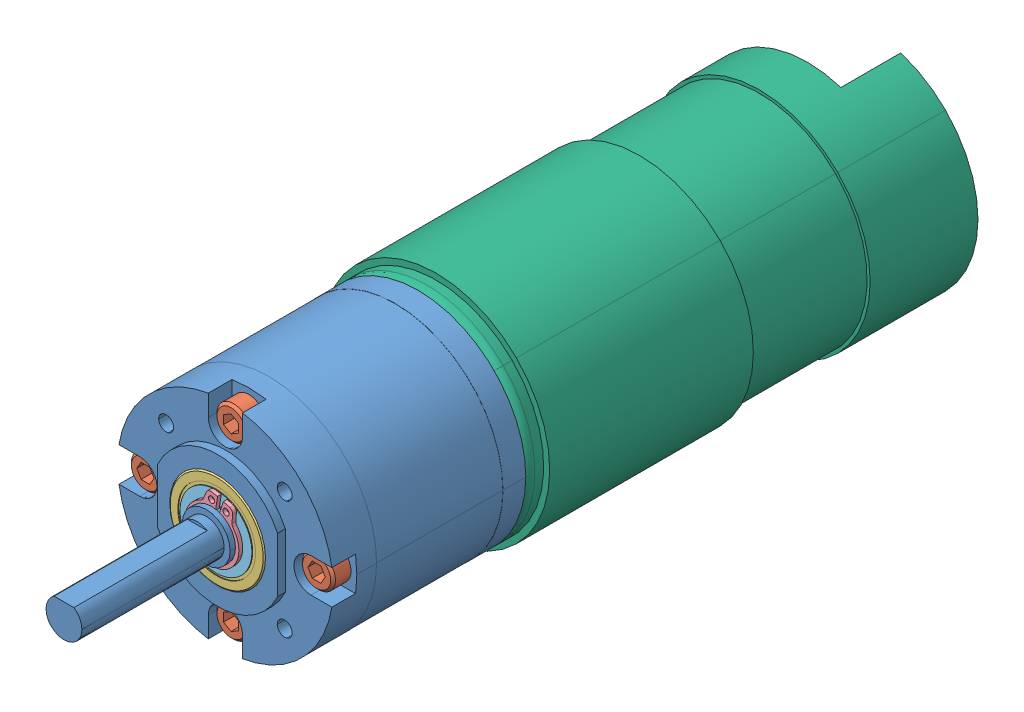
SolidWorks assembly am-3637+NeveRest+20+Orbital+Gearmotor (2).STEP, configuration Default. Lengths in mm.
Overall size (53.74 53.74 134.3).
9 component instances, 6 part files, 0 mates.
Components (placement in the parent):
- NeveRest orbital 2 stage Gearbox.STEP-1: NeveRest orbital 2 stage Gearbox.STEP [Default] at (-28.8441 -12.442 -2.3383) size (36 36 59.11)
- SHCS M3 x 16mm.STEP-1: SHCS M3 x 16mm.STEP [Default] at (-28.8441 1.8455 25.8811) size (5.5 5.5 19)
- SHCS M3 x 16mm.STEP-2: SHCS M3 x 16mm.STEP [Default] at (-14.5566 -12.442 25.8811) x (0 -1 0) z (0 0 1) size (5.5 5.5 19)
- SHCS M3 x 16mm.STEP-3: SHCS M3 x 16mm.STEP [Default] at (-28.8441 -26.7295 25.8811) x (-1 0 0) z (0 0 1) size (5.5 5.5 19)
- SHCS M3 x 16mm.STEP-4: SHCS M3 x 16mm.STEP [Default] at (-43.1316 -12.442 25.8811) x (0 1 0) z (0 0 1) size (5.5 5.5 19)
- 7804K117_STAINLESS STEEL BALL BEARING_7804K117.STEP-1: 7804K117_STAINLESS STEEL BALL BEARING_7804K117.STEP [Default] at (-28.8441 -12.442 28.7705) x (0.941717 0.336405 0) z (0 0 1) size (16 16 5)
- 97633A150_BLACK-FINISH STEEL EXTERNAL RETAINING RING_97633A150_grv.STEP-1: 97633A150_BLACK-FINISH STEEL EXTERNAL RETAINING RING_97633A150_grv.STEP [Default] at (-28.8441 -12.442 31.715) x (0 0 -1) z (0.971339 -0.2377 0) size (0.64 10.57 9.01)
- Shim.STEP-1: Shim.STEP [Default] at (-28.8441 -12.442 31.3975) x (1 0 0) z (0 1 0) size (12 0.13 12)
- am-3104 NeveRest Motor.STEP-1: am-3104 NeveRest Motor.STEP [Default] at (-28.8441 -12.442 -2.3303) x (0.707107 0.707107 0) z (0 0 1) size (38 38 85.19)
